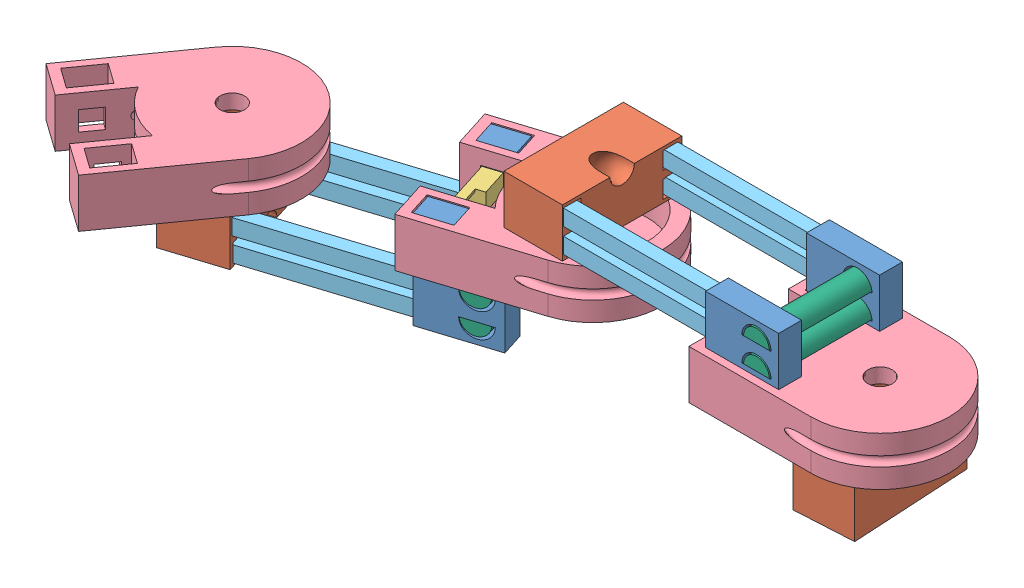
SolidWorks assembly Assem1, configuration Default. Lengths in mm.
Overall size (155.35 34.98 64.41).
24 component instances, 6 part files, 65 mates.
Components (placement in the parent):
- bar-1: bar [Default] at (1.8951 6.0809 13.3139) size (15 20 4.7)
- inner3-1: inner3 [Default] at (21.6451 8.0809 26.0139) x (0.998381 0 -0.056881) z (-0.056881 0 -0.998381) size (12.33 19.49 24.5)
- middle-1: middle [Default] at (1.7951 6.3309 19.0139) size (3.5 3.5 14)
- outer3-1: outer3 [Default] at (21.6451 1.0809 26.0139) x (-1 0 0) z (0 0 -1) size (39.2 10 28.4)
- bar-2: bar [Default] at (1.8951 6.0809 34.0139) size (15 20 4.7)
- connector-1: connector [Default] at (-36.4549 18.8031 36.4889) x (0 0 -1) z (1 0 0) size (2.75 3.25 40)
- connector-2: connector [Default] at (-36.4549 18.8031 15.7889) x (0 0 -1) z (1 0 0) size (2.75 3.25 40)
- connector-3: connector [Default] at (3.5451 13.8031 15.5389) x (0 0 1) z (-1 0 0) size (2.75 3.25 40)
- connector-4: connector [Default] at (-36.4549 13.8031 36.4889) x (0 0 -1) z (1 0 0) size (2.75 3.25 40)
- slide-1: slide [Default] at (8.9951 17.0809 13.7139) size (5.3 2.65 25)
- slide-2: slide [Default] at (8.9951 12.0809 13.7139) size (5.3 2.65 25)
- inner3-2: inner3 [Default] at (-37.4549 4.0781 25.8139) x (-1 0 0) z (0 0 -1) size (12.33 19.49 24.5)
- outer3-2: outer3 [Default] at (-37.4549 11.0781 25.8139) x (-0.953156 0 0.302479) z (0.302479 0 0.953156) size (39.2 10 28.4)
- connector-5: connector [Default] at (-51.2526 -1.6441 41.1823) x (-0.302479 0 -0.953156) z (-0.953156 0 0.302479) size (2.75 3.25 40)
- inner3-3: inner3 [Default] at (-93.44 8.0809 43.7903) x (-0.953156 0 0.302479) z (0.302479 0 0.953156) size (12.33 19.49 24.5)
- slide-3: slide [Default] at (-45.7011 0.0781 41.65) x (0.953156 0 -0.302479) z (-0.302479 0 -0.953156) size (5.3 2.65 25)
- outer3-3: outer3 [Default] at (-93.44 1.0809 43.7903) x (-0.579625 0 0.814883) z (-0.814883 0 -0.579625) size (39.2 10 28.4)
- connector-6: connector [Default] at (-95.911 -1.6441 33.6895) x (0.302479 0 0.953156) z (0.953156 0 -0.302479) size (2.75 3.25 40)
- connector-7: connector [Default] at (-89.4545 -6.6441 53.0432) x (0.302479 0 0.953156) z (0.953156 0 -0.302479) size (2.75 3.25 40)
- connector-8: connector [Default] at (-95.911 -6.6441 33.6895) x (0.302479 0 0.953156) z (0.953156 0 -0.302479) size (2.75 3.25 40)
- bar-3: bar [Default] at (-58.6088 6.0781 24.4485) x (0.953156 0 -0.302479) z (-0.302479 0 -0.953156) size (15 20 4.7)
- slide-4: slide [Default] at (-45.7011 -4.9219 41.65) x (0.953156 0 -0.302479) z (-0.302479 0 -0.953156) size (5.3 2.65 25)
- middle-2: middle [Default] at (-54.167 5.8281 38.7761) x (-0.953156 0 0.302479) z (-0.302479 0 -0.953156) size (3.5 3.5 14)
- bar-4: bar [Default] at (-52.1523 6.0781 43.8022) x (0.953156 0 -0.302479) z (-0.302479 0 -0.953156) size (15 20 4.7)
Mates (geometry in assembly coordinates):
- Coincident5: coincident anti-aligned: plane of bar-1 through (-1.4549 6.0809 18.0139) normal (-1 0 0); plane of outer3-1 through (-1.4549 1.0809 13.3139) normal (1 0 0)
- Coincident6: coincident anti-aligned: plane of bar-1 through (1.8951 11.0809 18.0139) normal (0 -1 0); plane of outer3-1 through (21.6451 11.0809 26.0139) normal (0 1 0)
- Coincident7: coincident anti-aligned: plane of bar-1 through (1.8951 6.0809 13.3139) normal (0 0 -1); plane of outer3-1 through (-1.4549 1.0809 13.3139) normal (0 0 1)
- Coincident8: coincident anti-aligned: plane of outer3-1 through (21.6451 11.0809 26.0139) normal (0 1 0); plane of bar-2 through (1.8951 11.0809 38.7139) normal (0 -1 0)
- Coincident9: coincident anti-aligned: plane of outer3-1 through (-1.4549 1.0809 38.7139) normal (0 0 -1); plane of bar-2 through (1.8951 6.0809 38.7139) normal (0 0 1)
- Coincident10: coincident anti-aligned: plane of outer3-1 through (-1.4549 1.0809 38.7139) normal (1 0 0); plane of bar-2 through (-1.4549 6.0809 38.7139) normal (-1 0 0)
- Coincident11: coincident anti-aligned: plane of middle-1 through (0.0451 8.0809 33.0139) normal (-1 0 0); plane of outer3-1 through (0.0451 8.0809 40.2149) normal (1 0 0)
- Coincident12: coincident anti-aligned: plane of middle-1 through (0.0451 8.0809 33.0139) normal (0 1 0); plane of outer3-1 through (4.0451 8.0809 40.2149) normal (0 -1 0)
- Distance1: distance = 1 mm anti-aligned: plane of middle-1 through (1.7951 6.3309 33.0139) normal (0 0 1); plane of bar-2 through (1.8951 6.0809 34.0139) normal (0 0 -1)
- Coincident14: coincident anti-aligned: circle of inner3-1; circle of outer3-1
- Coincident15: coincident anti-aligned: plane of bar-2 through (3.5451 6.0809 34.0139) normal (-1 0 0); plane of connector-1 through (3.5451 18.8031 36.4889) normal (1 0 0)
- Coincident16: coincident anti-aligned: plane of bar-2 through (3.5451 20.4281 37.8639) normal (0 0 -1); plane of connector-1 through (3.5451 20.4281 37.8639) normal (0 0 1)
- Coincident17: coincident anti-aligned: plane of bar-2 through (3.5451 20.4281 34.8639) normal (0 -1 0); plane of connector-1 through (3.5451 20.4281 37.8639) normal (0 1 0)
- Coincident18: coincident anti-aligned: plane of bar-1 through (3.5451 6.0809 13.3139) normal (-1 0 0); plane of connector-2 through (3.5451 18.8031 15.7889) normal (1 0 0)
- Coincident19: coincident anti-aligned: plane of bar-1 through (3.5451 20.4281 14.1639) normal (0 -1 0); plane of connector-2 through (3.5451 20.4281 17.1639) normal (0 1 0)
- Coincident20: coincident anti-aligned: plane of bar-1 through (3.5451 20.4281 17.1639) normal (0 0 -1); plane of connector-2 through (3.5451 20.4281 17.1639) normal (0 0 1)
- Coincident21: coincident anti-aligned: plane of bar-2 through (3.5451 6.0809 34.0139) normal (-1 0 0); plane of connector-4 through (3.5451 13.8031 36.4889) normal (1 0 0)
- Coincident22: coincident anti-aligned: plane of bar-2 through (3.5451 11.9281 37.8639) normal (0 0 -1); plane of connector-4 through (3.5451 15.4281 37.8639) normal (0 0 1)
- Coincident23: coincident anti-aligned: plane of bar-2 through (3.5451 15.4281 34.8639) normal (0 -1 0); plane of connector-4 through (3.5451 15.4281 37.8639) normal (0 1 0)
- Coincident24: coincident anti-aligned: plane of bar-1 through (3.5451 6.0809 13.3139) normal (-1 0 0); plane of connector-3 through (3.5451 13.8031 15.5389) normal (1 0 0)
- Coincident25: coincident anti-aligned: plane of bar-1 through (3.5451 11.9281 14.1639) normal (0 0 1); plane of connector-3 through (-36.4549 15.4281 14.1639) normal (0 0 -1)
- Coincident26: coincident anti-aligned: plane of bar-1 through (3.5451 15.4281 14.1639) normal (0 -1 0); plane of connector-3 through (-36.4549 15.4281 14.1639) normal (0 1 0)
- Coincident27: coincident aligned: plane of bar-2 through (1.8951 6.0809 38.7139) normal (0 0 1); plane of slide-1 through (8.9951 17.0809 38.7139) normal (0 0 1)
- Concentric1: concentric aligned: cylinder of bar-2 through (8.9951 17.0809 38.7139) axis (0 0 -1) radius 3; cylinder of slide-1 through (8.9951 17.0809 38.7139) axis (0 0 -1) radius 2.65
- Coincident28: coincident aligned: plane of bar-2 through (1.8951 6.0809 38.7139) normal (0 0 1); plane of slide-2 through (8.9951 12.0809 38.7139) normal (0 0 1)
- Concentric2: concentric aligned: cylinder of bar-2 through (8.9951 12.0809 38.7139) axis (0 0 -1) radius 3; cylinder of slide-2 through (8.9951 12.0809 38.7139) axis (0 0 -1) radius 2.65
- Coincident29: coincident anti-aligned: plane of connector-2 through (-36.4549 18.8031 15.7889) normal (-1 0 0); plane of inner3-2 through (-36.4549 4.0781 25.8139) normal (1 0 0)
- Coincident30: coincident anti-aligned: plane of connector-2 through (3.5451 20.4281 17.1639) normal (0 1 0); plane of inner3-2 through (-36.4549 20.4281 14.4139) normal (0 -1 0)
- Coincident31: coincident anti-aligned: plane of connector-2 through (3.5451 20.4281 14.4139) normal (0 0 -1); plane of inner3-2 through (-36.4549 20.4281 14.4139) normal (0 0 1)
- Concentric3: concentric anti-aligned: circle of inner3-2; circle of outer3-2
- Coincident32: coincident anti-aligned: plane of inner3-2 through (-37.4549 4.0781 25.8139) normal (0 -1 0); plane of outer3-2 through (-37.4549 4.0781 25.8139) normal (0 1 0)
- Concentric4: concentric anti-aligned: circle of inner3-3; circle of outer3-3
- Distance2: distance = 1 mm anti-aligned: plane of middle-2 through (-58.4017 5.8281 25.4319) normal (-0.302479 0 -0.953156); plane of bar-3 through (-58.6088 6.0781 24.4485) normal (0.302479 0 0.953156)
- Coincident36: coincident aligned: plane of bar-3 through (-60.0305 6.0781 19.9687) normal (-0.302479 0 -0.953156); plane of slide-4 through (-53.2631 -4.9219 17.8211) normal (-0.302479 0 -0.953156)
- Coincident43: coincident anti-aligned: plane of connector-6 through (-57.7848 -1.6441 21.5904) normal (0.953156 0 -0.302479); plane of bar-3 through (-57.0361 6.0781 23.9494) normal (-0.953156 0 0.302479)
- Coincident44: coincident anti-aligned: plane of inner3-3 through (-89.0386 -8.2691 54.3538) normal (0 1 0); plane of connector-7 through (-51.7442 -8.2691 39.6334) normal (0 -1 0)
- Coincident45: coincident anti-aligned: plane of connector-8 through (-58.2007 -8.2691 20.2798) normal (-0.302479 0 -0.953156); plane of bar-3 through (-58.2007 -8.2691 20.2798) normal (0.302479 0 0.953156)
- Coincident46: coincident anti-aligned: plane of connector-8 through (-58.2007 -8.2691 20.2798) normal (0 -1 0); plane of bar-3 through (-57.2932 -8.2691 23.1393) normal (0 1 0)
- Concentric5: concentric aligned: cylinder of slide-3 through (-53.2631 0.0781 17.8211) axis (0.302479 0 0.953156) radius 2.65; cylinder of bar-3 through (-53.2631 0.0781 17.8211) axis (0.302479 0 0.953156) radius 3
- Coincident47: coincident anti-aligned: plane of connector-7 through (-51.7442 -8.2691 39.6334) normal (0 -1 0); plane of bar-4 through (-50.8367 -8.2691 42.4929) normal (0 1 0)
- Coincident49: coincident anti-aligned: plane of connector-7 through (-51.3283 -6.6441 40.944) normal (0.953156 0 -0.302479); plane of bar-4 through (-50.5796 6.0781 43.3031) normal (-0.953156 0 0.302479)
- Coincident50: coincident anti-aligned: plane of connector-8 through (-57.7848 -6.6441 21.5904) normal (0.953156 0 -0.302479); plane of bar-3 through (-57.0361 6.0781 23.9494) normal (-0.953156 0 0.302479)
- Coincident51: coincident anti-aligned: plane of inner3-3 through (-89.0386 -8.2691 54.3538) normal (-0.302479 0 -0.953156); plane of connector-7 through (-50.9123 -8.2691 42.2546) normal (0.302479 0 0.953156)
- Coincident52: coincident anti-aligned: plane of connector-6 through (-58.2007 -3.2691 20.2798) normal (-0.302479 0 -0.953156); plane of bar-3 through (-58.2007 0.2309 20.2798) normal (0.302479 0 0.953156)
- Coincident53: coincident anti-aligned: plane of inner3-3 through (-92.4869 8.0809 43.4878) normal (0.953156 0 -0.302479); plane of connector-7 through (-89.4545 -6.6441 53.0432) normal (-0.953156 0 0.302479)
- Coincident54: coincident anti-aligned: plane of connector-6 through (-58.2007 -3.2691 20.2798) normal (0 -1 0); plane of bar-3 through (-57.2932 -3.2691 23.1393) normal (0 1 0)
- Coincident55: coincident anti-aligned: plane of connector-7 through (-51.7442 -8.2691 39.6334) normal (-0.302479 0 -0.953156); plane of bar-4 through (-51.7442 -8.2691 39.6334) normal (0.302479 0 0.953156)
- Coincident56: coincident anti-aligned: plane of connector-5 through (-51.2526 -1.6441 41.1823) normal (0.953156 0 -0.302479); plane of bar-4 through (-50.5796 6.0781 43.3031) normal (-0.953156 0 0.302479)
- Coincident57: coincident anti-aligned: plane of connector-5 through (-88.963 -3.2691 54.592) normal (0 -1 0); plane of bar-4 through (-50.8367 -3.2691 42.4929) normal (0 1 0)
- Coincident58: coincident anti-aligned: plane of connector-5 through (-88.963 -3.2691 54.592) normal (0.302479 0 0.953156); plane of bar-4 through (-50.8367 0.2309 42.4929) normal (-0.302479 0 -0.953156)
- Coincident59: coincident aligned: plane of slide-3 through (-53.2631 0.0781 17.8211) normal (-0.302479 0 -0.953156); plane of bar-3 through (-60.0305 6.0781 19.9687) normal (-0.302479 0 -0.953156)
- Concentric6: concentric aligned: cylinder of bar-3 through (-53.2631 -4.9219 17.8211) axis (0.302479 0 0.953156) radius 3; cylinder of slide-4 through (-53.2631 -4.9219 17.8211) axis (0.302479 0 0.953156) radius 2.65
- Coincident62: coincident anti-aligned: plane of outer3-2 through (-55.6313 11.0781 44.9062) normal (-0.302479 0 -0.953156); plane of bar-4 through (-52.1523 6.0781 43.8022) normal (0.302479 0 0.953156)
- Coincident63: coincident aligned: plane of outer3-2 through (-37.4549 11.0781 25.8139) normal (0 1 0); plane of bar-4 through (-53.574 11.0781 39.3223) normal (0 1 0)
- Coincident64: coincident anti-aligned: plane of outer3-2 through (-48.9593 11.0781 42.7889) normal (-0.953156 0 0.302479); plane of bar-4 through (-50.3809 6.0781 38.309) normal (0.953156 0 -0.302479)
- Coincident66: coincident aligned: plane of outer3-2 through (-37.4549 11.0781 25.8139) normal (0 1 0); plane of bar-3 through (-60.0305 11.0781 19.9687) normal (0 1 0)
- Coincident67: coincident anti-aligned: plane of outer3-2 through (-63.3143 11.0781 20.696) normal (0.953156 0 -0.302479); plane of bar-3 through (-63.2236 6.0781 20.982) normal (-0.953156 0 0.302479)
- Parallel2: parallel anti-aligned: plane of inner3-3 through (-95.0277 -8.2691 35.4813) normal (-0.302479 0 -0.953156); plane of connector-8 through (-57.3689 -8.2691 22.901) normal (0.302479 0 0.953156)
- Coincident69: coincident anti-aligned: plane of bar-3 through (-60.0305 -4.9219 19.9687) normal (0 -1 0); plane of slide-4 through (-55.789 -4.9219 18.6227) normal (0 1 0)
- Coincident70: coincident anti-aligned: plane of slide-3 through (-55.789 0.0781 18.6227) normal (0 1 0); plane of bar-4 through (-53.574 0.0781 39.3223) normal (0 -1 0)
- Parallel3: parallel anti-aligned: plane of bar-3 through (-58.6088 6.0781 24.4485) normal (0.302479 0 0.953156); plane of middle-2 through (-58.4017 5.8281 25.4319) normal (-0.302479 0 -0.953156)
- Coincident73: coincident anti-aligned: plane of outer3-2 through (-53.7476 4.0781 45.8832) normal (0.953156 0 -0.302479); plane of middle-2 through (-60.0697 7.5781 25.9613) normal (-0.953156 0 0.302479)
- Coincident74: coincident anti-aligned: plane of outer3-2 through (-49.935 4.0781 44.6733) normal (0 1 0); plane of middle-2 through (-56.7337 4.0781 24.9026) normal (0 -1 0)
- Coincident75: coincident anti-aligned: plane of inner3-3 through (-93.44 8.0809 43.7903) normal (0 1 0); plane of outer3-3 through (-93.44 8.0809 43.7903) normal (0 -1 0)
- Coincident76: coincident anti-aligned: plane of outer3-2 through (-61.8019 11.0781 25.4618) normal (-0.302479 0 -0.953156); plane of bar-3 through (-58.6088 6.0781 24.4485) normal (0.302479 0 0.953156)
